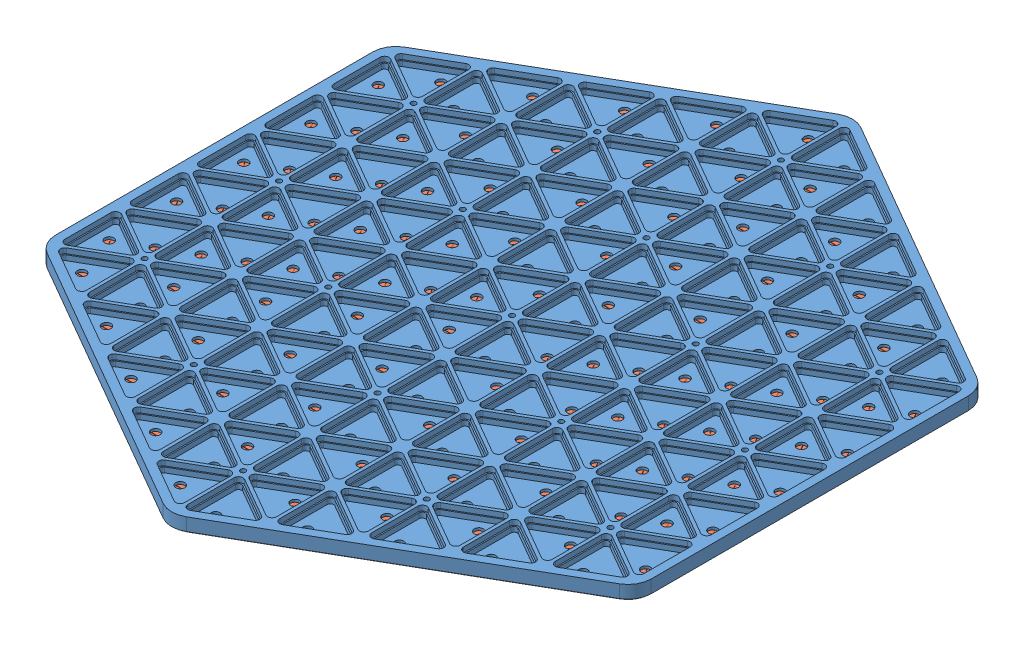
SolidWorks assembly PanelAssy, configuration Default. Lengths in mm.
Overall size (590.55 21.59 674.84).
2 component instances, 2 part files, 4 mates.
Components (placement in the parent):
- WS2812 Panel-1: WS2812 Panel [Default] at (151.1306 391.5826 537.9174) size (590.55 12.7 674.84)
- Part1^PanelAssy-1: Part1^PanelAssy [Default] at (151.1306 391.5826 537.9174) x (-1 0 0) z (0 -1 0) size (584.2 668.49 8.89) (virtual)
Mates (geometry in assembly coordinates):
- InPlace1: in place: plane of WS2812 Panel-1 through (151.1306 391.5826 537.9174) normal (0 -1 0); plane of ? through (0 391.5826 0) normal (0 -1 0); moOrthogonalPlaneRef_w of WS2812 Panel-1 through (151.1306 391.5826 537.9174) normal (0 -1 0); unknown of ?; plane of WS2812 Panel-1 through (151.1306 391.5826 537.9174) normal (0 -1 0); line of ? through (-55 0 391.5826) axis (0 -1 0); plane of WS2812 Panel-1 through (151.1306 391.5826 537.9174) normal (0 -1 0); unknown of Part1^PanelAssy-1
- Coincident1: coincident aligned: 
- Coincident2: coincident aligned: plane of WS2812 Panel-1 through (151.1306 391.5826 537.9174) normal (0 0 -1); unknown of Part1^PanelAssy-1
- Coincident3: coincident anti-aligned: plane of WS2812 Panel-1 through (151.1306 391.5826 537.9174) normal (1 0 0); unknown of Part1^PanelAssy-1
